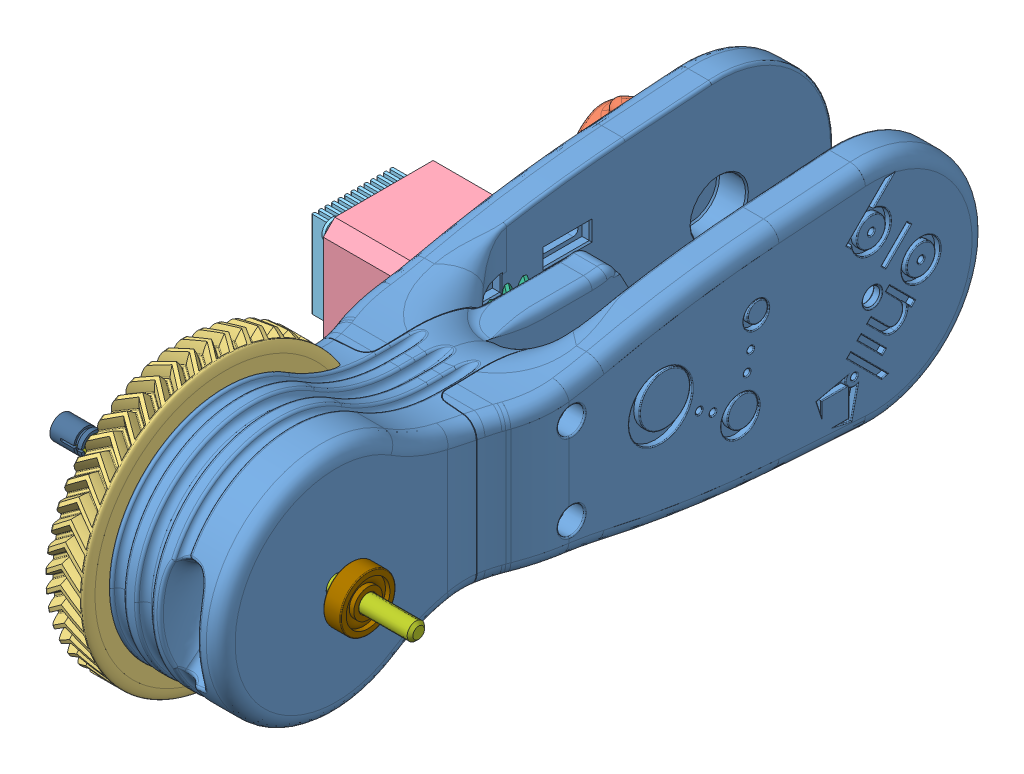
SolidWorks assembly 4 Arm1b, configuration Domyślna. Lengths in mm.
Overall size (129 97.66 268.5).
14 component instances, 11 part files, 15 mates.
Components (placement in the parent):
- 4 beta-1: 4 beta [Domyślna] at origin size (91.84 82.94 268.5)
- 3.4.1 Encoder holder-1: 3.4.1 Encoder holder [Domyślna] at (-38 0 -179) x (0 -1 0) z (1 0 0) size (40 60 25.11)
- 4.1.3b ISO - RH Helical gear 1.5M 50T 37HA 20PA 6FW ---50A75H50L70.0N-1: 4.1.3b ISO - RH Helical gear 1.5M 50T 37HA 20PA 6FW ---50A75H50L70.0N [ISO - RH Helical gear 1.5M 50T 37HA 20PA 6FW ---50A75H50L70.0N] at (-20.5 0 0) x (1 0 0) z (0 0 -1) size (14.85 97.66 91.97)
- 4.2 MotorAssembly-1: 4.2 MotorAssembly [Domyślna] at (-30 0 -106) x (0 0 1) z (-1 0 0) size (42 42 67.27)
  - 2.2.1 Nema 17 x 33-1: 2.2.1 Nema 17 x 33 [Default] at origin size (42 42 56.05)
  - 3.2.2 radiator-1: 3.2.2 radiator [Domyślna] at (-0.0002 -0.0002 33) x (0 1 0) z (1 0 0) size (40.94 11 40.94)
  - 4.2.2 ISO - LH Helical gear 1.5M 15T 37HA 20PA 6FW ---15A75H50L8.0N-1: 4.2.2 ISO - LH Helical gear 1.5M 15T 37HA 20PA 6FW ---15A75H50L8.0N [ISO - LH Helical gear 1.5M 15T 37HA 20PA 6FW ---15A75H50L8.0N] at (0 0 -23.05) x (0 0 1) z (-0.949504 0.313755 0) size (12.44 31.23 31.24)
- 4.4 Shaft arm1-arm2-1: 4.4 Shaft arm1-arm2 [Domyślna] x (1 0 0) z (0 -1 0) size (123.6 30 19)
  - 4.4.1 Shaft 6x120-1: 4.4.1 Shaft 6x120 [Domyślna] x (0 0 -1) z (-1 0 0) size (6 6 120)
  - 4.4.2 Peg-1: 4.4.2 Peg [Domyślna] at origin size (2 30 2)
  - 4.4.3 ISO 15 RBB - 026 - 8,SI,NC,8_68-3: 4.4.3 ISO 15 RBB - 026 - 8,SI,NC,8_68 [ISO 15 RBB - 026 - 8,SI,NC,8_68] at (-34.5 0 0) x (-1 0 0) z (0 0 1) size (6 19 19)
  - 4.4.3 ISO 15 RBB - 026 - 8,SI,NC,8_68-2: 4.4.3 ISO 15 RBB - 026 - 8,SI,NC,8_68 [ISO 15 RBB - 026 - 8,SI,NC,8_68] at (34.5 0 0) x (-1 0 0) z (0 0 -1) size (6 19 19)
  - 3.3.2 Encoder_plastic_hub-1: 3.3.2 Encoder_plastic_hub [Domyślna] at (-57.6 0 0) x (0 1 0) z (0 0 1) size (8.2 11 8.2)
- 2.4.1 Encoder_main_housing-1: 2.4.1 Encoder_main_housing [Domyślna] at (-38 0 -179) x (0 -1 0) z (0 0 -1) size (23 21.6 23)
Mates (geometry in assembly coordinates):
- Wspólnie1: coordinate: point of 4 beta-1; point of assembly
- Wspólnie2: coincident anti-aligned: plane of 4 beta-1 through (-14.5 0 0) normal (-1 0 0); plane of 4.1.3b ISO - RH Helical gear 1.5M 50T 37HA 20PA 6FW ---50A75H50L70.0N-1 through (-14.5 0 0) normal (1 0 0)
- Koncentryczne1: concentric anti-aligned: cylinder of 4 beta-1 through (-26.5 0 0) axis (1 0 0) radius 35; cylinder of 4.1.3b ISO - RH Helical gear 1.5M 50T 37HA 20PA 6FW ---50A75H50L70.0N-1 through (42 0 0) axis (-1 0 0) radius 35
- Wspólnie3: coincident anti-aligned: plane of 4 beta-1 through (-26.5 12.1967 -12.1967) normal (0 0.707107 -0.707107); plane of 4.1.3b ISO - RH Helical gear 1.5M 50T 37HA 20PA 6FW ---50A75H50L70.0N-1 through (9.9605 12.1967 -12.1967) normal (0 -0.707107 0.707107)
- Wspólnie4: coincident anti-aligned: plane of 4 beta-1 through (-33 40 -179) normal (-1 0 0); plane of 3.4.1 Encoder holder-1 through (-33 0 -179) normal (1 0 0)
- Koncentryczne2: concentric anti-aligned: cylinder of 4 beta-1 through (-33 0 -179) axis (1 0 0) radius 3; cylinder of 3.4.1 Encoder holder-1 through (-33 0 -179) axis (-1 0 0) radius 6.2
- Wspólnie5: coincident anti-aligned: plane of 4 beta-1 through (0 0 0) normal (0 1 0); plane of 3.4.1 Encoder holder-1 through (-38 0 -179) normal (0 -1 0)
- Wspólnie6: coincident anti-aligned: plane of 4 beta-1 through (-30 40 -179) normal (-1 0 0); plane of 4.2 MotorAssembly-1/2.2.1 Nema 17 x 33-1 through (-30 0 -106) normal (1 0 0)
- Wspólnie7: coincident aligned: plane of 4.2 MotorAssembly-1/2.2.1 Nema 17 x 33-1 through (-30 0 -106) normal (0 1 0); plane of assembly through (0 0 0) normal (0 1 0)
- Szczelina1: slot anti-aligned: cylinder of 4.2 MotorAssembly-1/2.2.1 Nema 17 x 33-1 through (-63 15.5 -90.5) axis (1 0 0) radius 1.5; cylinder of 4 beta-1 through (33 15.5 -90.5) axis (-1 0 0) radius 1.6; cylinder of 4 beta-1 through (33 15.5 -100.5) axis (-1 0 0) radius 1.6
- Koncentryczne3: concentric aligned: cylinder of 4 beta-1 through (-33 0 0) axis (1 0 0) radius 3; cylinder of 4.4 Shaft arm1-arm2-1/4.4.1 Shaft 6x120-1 through (-65 0 0) axis (1 0 0) radius 3
- Koncentryczne4: concentric anti-aligned: cylinder of 4 beta-1 through (0 0 -16) axis (0 0 1) radius 1.05; cylinder of 4.4 Shaft arm1-arm2-1/4.4.2 Peg-1 through (0 0 15) axis (0 0 -1) radius 1
- Koncentryczne5: concentric anti-aligned: cylinder of 2.4.1 Encoder_main_housing-1 through (-38 4.25 -186.3612) axis (1 0 0) radius 1.1; cylinder of 3.4.1 Encoder holder-1 through (-32.999 4.25 -186.3612) axis (-1 0 0) radius 1.1
- Koncentryczne6: concentric anti-aligned: cylinder of 3.4.1 Encoder holder-1 through (-32.999 -4.25 -171.6388) axis (-1 0 0) radius 1.1; cylinder of 2.4.1 Encoder_main_housing-1 through (-38 -4.25 -171.6388) axis (1 0 0) radius 1.1
- Wspólnie8: coincident anti-aligned: plane of 3.4.1 Encoder holder-1 through (-38 0 -179) normal (-1 0 0); plane of 2.4.1 Encoder_main_housing-1 through (-38 0 -179) normal (1 0 0)
